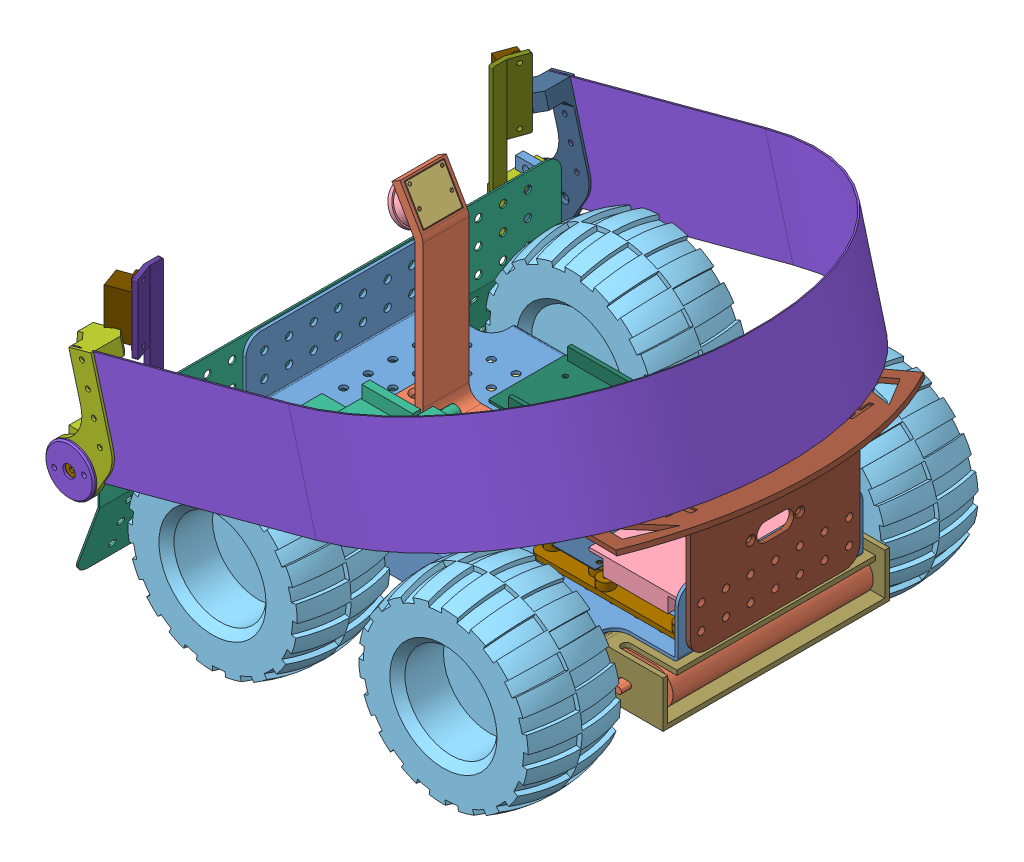
SolidWorks assembly Robot assembly, configuration Défaut. Lengths in mm.
Overall size (358.46 247.89 317.8).
40 component instances, 29 part files, 110 mates.
Components (placement in the parent):
- base-1: base [Défaut] at origin size (282.75 68.75 152.75)
- Battery-1: Battery [Default] at (120.5 -17 0) x (0 0 -1) z (1 0 0) size (145 23 45)
- motor-1: motor [Varsayılan] at (34.1153 -27.0341 -22.5727) x (-1 0 0) z (0 0 -1) size (24.4 24.4 69.3)
- motor-2: motor [Varsayılan] at (-115.8847 -27.0341 -22.5727) x (-1 0 0) z (0 0 -1) size (24.4 24.4 69.3)
- motor-3: motor [Varsayılan] at (115.8847 -27.0341 22.5727) size (24.4 24.4 69.3)
- motor-4: motor [Varsayılan] at (-34.1153 -27.0341 22.5727) size (24.4 24.4 69.3)
- Motor controller-1: Motor controller [Default] at (104.3727 13 0) x (0 0 1) z (-1 0 0) size (101.6 12 60.32)
- wheel-5: wheel [Default] at (-75.2588 -16.8727 115.8727) x (0 0 1) z (-1 0 0) size (69 120 120)
- wheel-6: wheel [Default] at (74.7412 -16.8727 115.8727) x (0 0 1) z (-0.999757 -0.022063 0) size (69 120 120)
- wheel-7: wheel [Default] at (-74.7412 -16.8727 -115.8727) x (0 0 -1) z (0.923728 0.383049 0) size (69 120 120)
- wheel-8: wheel [Default] at (75.2588 -16.8727 -115.8727) x (0 0 -1) z (0.974576 0.224058 0) size (69 120 120)
- plow-1: plow [Default] at (-145.3727 -12.6273 0) x (0 0 1) z (0 -1 0) size (300 18.07 97.16)
- Servo motor-1: Servo motor [Default] at (-155.3727 11.3727 119.9) x (-1 0 0) z (0 0 1) size (14 29 36)
- Servo motor-2: Servo motor [Default] at (-155.3727 11.3727 -119.9) x (1 0 0) z (0 0 -1) size (14 29 36)
- Cage-1: Cage [Default] at (1.6189 44.7973 0) x (0 0 1) z (-0.965926 -0.258819 0) size (310.66 70 301.4)
- H-bridge_support-1: H-bridge_support [Default] at (84.3727 0 0) x (0 0 1) z (-1 0 0) size (100 8 100)
- Fuse board-1: Fuse board [Default] at (58.3727 8 24.5) x (0 0 -1) z (1 0 0) size (49 0.5 36)
- Power board-1: Power board [Default] at (48.8727 8 -25) x (0 0 -1) z (1 0 0) size (50 1.06 25)
- Battery holder-1: Battery holder [Default] at (120 -32 0) x (0 0 -1) z (1 0 0) size (147 30 50)
- hex nut style 1 gradeab_iso-1: hex nut style 1 gradeab_iso [Hexagon Nut ISO - 4032 - M4 - W - N] at (120 3.2 -32) x (1 0 0) z (0 1 0) size (7 8.08 3.2)
- PRismino support-1: PRismino support [Default] at (-32 0 -40) x (0 0 1) z (-1 0 0) size (36 8 36)
- PRismino-1: PRismino [Default] at (-32 8 -40) x (0 0 1) z (-1 0 0) size (50 9.6 50)
- IR sensor support left-1: IR sensor support left [Défaut] at (-140.9264 106.3727 -127.6899) x (0 -1 0) z (-0.939693 0 -0.34202) size (100 22.4 6.07)
- IR sensor support right-1: IR sensor support right [Défaut] at (-143.7455 106.3727 129.7421) x (0 -1 0) z (0.939693 0 -0.34202) size (100 22.4 6.07)
- IR sensor-1: IR sensor [Default] at (-145.9686 83.8727 -122.608) x (0 -1 0) z (-0.939693 0 -0.34202) size (44.6 13 14)
- IR sensor-2: IR sensor [Default] at (-145.9686 83.8727 123.6341) x (0 -1 0) z (-0.939693 0 0.34202) size (44.6 13 14)
- Servo motor mount-1: Servo motor mount [Default] at (-145.3727 -11.1273 -117.9) x (0 1 0) z (-1 0 0) size (45 24 15.8)
- Servo motor mount-2: Servo motor mount [Default] at (-145.3727 33.8727 117.9) x (0 -1 0) z (-1 0 0) size (45 24 15.8)
- Camera support-1: Camera support [Default] at (-72 0 0) x (0 0 1) z (-1 0 0) size (30 133.98 45)
- Raspberry Pi camera-1: Raspberry Pi camera [Default] at (-77.4378 122.0885 0) x (0 0 1) z (0.5 -0.866025 0) size (25 6 24)
- Lens-1: Lens [Default] at (-81.134 116.4904 0) x (-0.5 0.866025 0) z (0 0 1) size (25 15 25)
- Raspberry Pi support-1: Raspberry Pi support [Default] at (-56 0 48) x (-1 0 0) z (0 0 -1) size (67.8 8 35.5)
- Raspberry Pi-1: Raspberry Pi [Default] at (-56 8 48) size (110.9 20.5 65.5)
- Cage servo support left-1: Cage servo support left [Default] at (-155.3727 6.8727 152.9) x (0 0 1) z (0.965926 0.258819 0) size (24 82 46.38)
- Cage servo support blocker-1: Cage servo support blocker [Default] at (-155.3727 6.8727 156.9) x (0 0 1) z (0.965926 0.258819 0) size (2 32 32)
- Servo adapter-1: Servo adapter [Default] at (-155.3727 6.8727 156.4) x (0.961499 0.274807 0) z (0 0 -1) size (8 28.8 4.8)
- Cage servo support right-2: Cage servo support right [Default] at (-155.3727 6.8727 -152.9) x (0 0 1) z (0.965926 0.258819 0) size (24 82 46.38)
- Servo adapter-2: Servo adapter [Default] at (-155.3727 6.8727 -156.4) x (-0.961499 -0.274807 0) z (0 0 1) size (8 28.8 4.8)
- Cage servo support blocker-2: Cage servo support blocker [Default] at (-155.3727 6.8727 -156.9) x (0 0 -1) z (-0.965926 -0.258819 0) size (2 32 32)
- Cage rear support-1: Cage rear support [Default] at (141.3727 39 0) x (0 0 -1) z (1 0 0) size (200 89.91 70.32)
Mates (geometry in assembly coordinates):
- Coincident4: coincident anti-aligned: plane of Battery-1 through (120.5 -17 0) normal (0 0 -1); plane of assembly through (0 0 0) normal (0 0 1)
- Concentric1: concentric aligned: cylinder of base-1 through (-83.5 -16.8727 74.3727) axis (0 0 1) radius 1.6; cylinder of motor-4 through (-83.5 -16.8727 64.3727) axis (0 0 1) radius 1
- Concentric2: concentric aligned: cylinder of base-1 through (-66.5 -16.8727 74.3727) axis (0 0 1) radius 1.6; cylinder of motor-4 through (-66.5 -16.8727 64.3727) axis (0 0 1) radius 1
- Coincident5: coincident anti-aligned: plane of base-1 through (0 73.6273 74.3727) normal (0 0 -1); plane of motor-4 through (-75.2588 -16.8727 74.3727) normal (0 0 1)
- Concentric3: concentric aligned: cylinder of base-1 through (66.5 -16.8727 74.3727) axis (0 0 1) radius 1.6; cylinder of motor-3 through (66.5 -16.8727 64.3727) axis (0 0 1) radius 1
- Concentric4: concentric aligned: cylinder of base-1 through (83.5 -16.8727 74.3727) axis (0 0 1) radius 1.6; cylinder of motor-3 through (83.5 -16.8727 64.3727) axis (0 0 1) radius 1
- Coincident6: coincident anti-aligned: plane of base-1 through (0 73.6273 74.3727) normal (0 0 -1); plane of motor-3 through (74.7412 -16.8727 74.3727) normal (0 0 1)
- Concentric5: concentric aligned: cylinder of base-1 through (83.5 -16.8727 -74.3727) axis (0 0 -1) radius 1.6; cylinder of motor-1 through (83.5 -16.8727 -64.3727) axis (0 0 -1) radius 1
- Concentric6: concentric aligned: cylinder of base-1 through (66.5 -16.8727 -74.3727) axis (0 0 -1) radius 1.6; cylinder of motor-1 through (66.5 -16.8727 -64.3727) axis (0 0 -1) radius 1
- Coincident7: coincident anti-aligned: plane of base-1 through (0 73.6273 -74.3727) normal (0 0 1); plane of motor-1 through (75.2588 -16.8727 -74.3727) normal (0 0 -1)
- Concentric7: concentric aligned: cylinder of motor-2 through (-66.5 -16.8727 -64.3727) axis (0 0 -1) radius 1; cylinder of base-1 through (-66.5 -16.8727 -74.3727) axis (0 0 -1) radius 1.6
- Concentric8: concentric aligned: cylinder of base-1 through (-83.5 -16.8727 -74.3727) axis (0 0 -1) radius 1.6; cylinder of motor-2 through (-83.5 -16.8727 -64.3727) axis (0 0 -1) radius 1
- Coincident8: coincident anti-aligned: plane of base-1 through (0 73.6273 -74.3727) normal (0 0 1); plane of motor-2 through (-74.7412 -16.8727 -74.3727) normal (0 0 -1)
- Coincident15: coincident aligned: plane of Motor controller-1 through (104.3727 13 0) normal (0 0 1); plane of assembly through (0 0 0) normal (0 0 1)
- Concentric18: concentric anti-aligned: cylinder of motor-1 through (75.2588 -16.8727 -85.8727) axis (0 0 1) radius 2; cylinder of wheel-8 through (75.2588 -16.8727 -76.8727) axis (0 0 -1) radius 5
- Coincident26: coincident anti-aligned: plane of motor-1 through (75.2588 -16.8727 -76.8727) normal (0 0 -1); plane of wheel-8 through (75.2588 -16.8727 -76.8727) normal (0 0 1)
- Coincident28: coincident aligned: plane of plow-1; plane of assembly through (0 0 0) normal (0 0 1)
- Concentric20: concentric anti-aligned: cylinder of base-1 through (-141.3727 27.3727 0) axis (1 0 0) radius 2.4; cylinder of plow-1 through (-144.3727 27.3727 0) axis (-1 0 0) radius 2.4
- Coincident37: coincident aligned: plane of Cage-1; plane of assembly through (0 0 0) normal (0 0 1)
- Distance13: distance = 3 mm anti-aligned: plane of base-1 through (-141.3727 -140.6273 0) normal (-1 0 0); plane of plow-1 through (-144.3727 -52.6273 -140) normal (1 0 0)
- Coincident45: coincident anti-aligned: plane of base-1 through (0 0 0) normal (0 1 0); plane of H-bridge_support-1 through (84.3727 0 0) normal (0 -1 0)
- Distance5: distance = 5 mm anti-aligned: plane of H-bridge_support-1 through (134.3727 3 -50) normal (1 0 0); plane of base-1 through (139.3727 -140.6273 0) normal (-1 0 0)
- Coincident47: coincident aligned: plane of H-bridge_support-1 through (84.3727 0 0) normal (0 0 1); plane of assembly through (0 0 0) normal (0 0 1)
- Concentric25: concentric anti-aligned: cylinder of Motor controller-1 through (79.3727 13 -45) axis (0 1 0) radius 1.5; cylinder of H-bridge_support-1 through (79.3727 8 -45) axis (0 -1 0) radius 5
- Distance6: distance = 10 mm anti-aligned: plane of H-bridge_support-1 through (84.3727 3 0) normal (0 1 0); plane of Motor controller-1 through (104.3727 13 0) normal (0 -1 0)
- Distance9: distance = 2 mm aligned: plane of H-bridge_support-1 through (34.3727 3 -50) normal (-1 0 0); plane of Fuse board-1 through (36.3727 18.2082 12) normal (-1 0 0)
- Distance7: distance = 5 mm aligned: plane of Fuse board-1 through (44.3727 8.5 45) normal (0 0 1); plane of H-bridge_support-1 through (34.3727 3 50) normal (0 0 1)
- Coincident52: coincident anti-aligned: plane of H-bridge_support-1 through (39.6227 8 39.5) normal (0 1 0); plane of Fuse board-1 through (58.3727 8 24.5) normal (0 -1 0)
- Distance11: distance = 2 mm aligned: plane of H-bridge_support-1 through (34.3727 3 -50) normal (-1 0 0); plane of Power board-1 through (36.3727 9.06 0) normal (-1 0 0)
- Coincident55: coincident aligned: plane of H-bridge_support-1 through (34.3727 3 -50) normal (0 0 -1); plane of Power board-1 through (36.3727 9.06 -50) normal (0 0 -1)
- Coincident56: coincident anti-aligned: plane of H-bridge_support-1 through (41.3727 8 -15) normal (0 1 0); plane of Power board-1 through (48.8727 8 -25) normal (0 -1 0)
- Coincident60: coincident anti-aligned: plane of base-1 through (0 -2 0) normal (0 -1 0); plane of Battery holder-1 through (120 -2 0) normal (0 1 0)
- Coincident61: coincident anti-aligned: plane of Battery holder-1 through (120 -32 0) normal (0 0 -1); plane of assembly through (0 0 0) normal (0 0 1)
- Distance12: distance = 12 mm anti-aligned: plane of Battery-1; plane of Battery holder-1 through (120 -5 0) normal (0 -1 0)
- Tangent9: tangent anti-aligned: cylinder of Battery-1 through (109.5 -17 65) axis (0 0 -1) radius 11.5; plane of Battery holder-1 through (98 -2 73.5) normal (1 0 0)
- Concentric28: concentric anti-aligned: cylinder of base-1 through (120 -2 32) axis (0 1 0) radius 2.4; cylinder of Battery holder-1 through (120 -5 32) axis (0 -1 0) radius 2.25
- Concentric29: concentric aligned: cylinder of base-1 through (120 -2 -32) axis (0 1 0) radius 2.4; cylinder of hex nut style 1 gradeab_iso-1 through (120 0 -32) axis (0 1 0) radius 1.65
- Coincident64: coincident anti-aligned: plane of base-1 through (0 0 0) normal (0 1 0); plane of hex nut style 1 gradeab_iso-1 through (113 0 -32) normal (0 -1 0)
- Coincident66: coincident anti-aligned: plane of PRismino support-1 through (-19 8 -27) normal (0 1 0); plane of PRismino-1 through (-32 8 -40) normal (0 -1 0)
- Concentric32: concentric aligned: cylinder of PRismino support-1 through (-19 0 -27) axis (0 1 0) radius 1.45; cylinder of PRismino-1 through (-19 8 -27) axis (0 1 0) radius 1.6
- Concentric33: concentric aligned: cylinder of PRismino support-1 through (-45 0 -53) axis (0 1 0) radius 1.45; cylinder of PRismino-1 through (-45 8 -53) axis (0 1 0) radius 1.6
- Coincident67: coincident anti-aligned: plane of base-1 through (0 0 0) normal (0 1 0); plane of PRismino support-1 through (-19 0 -27) normal (0 -1 0)
- Concentric42: concentric anti-aligned: cylinder of plow-1 through (-144.3727 11.3727 112) axis (-1 0 0) radius 2.4; cylinder of IR sensor support right-1 through (-151.4057 11.3727 112) axis (1 0 0) radius 2.25
- Coincident68: coincident anti-aligned: plane of plow-1 through (-145.3727 -52.6273 -140) normal (-1 0 0); plane of IR sensor support right-1 through (-145.3727 6.3727 107.5261) normal (1 0 0)
- Concentric43: concentric anti-aligned: cylinder of plow-1 through (-144.3727 27.3727 112) axis (-1 0 0) radius 2.4; cylinder of IR sensor support right-1 through (-151.4057 27.3727 112) axis (1 0 0) radius 2.25
- Concentric44: concentric aligned: cylinder of plow-1 through (-144.3727 11.3727 -112) axis (-1 0 0) radius 2.4; cylinder of IR sensor support left-1 through (-138.0422 11.3727 -112) axis (-1 0 0) radius 2.25
- Coincident69: coincident anti-aligned: plane of plow-1 through (-145.3727 -52.6273 -140) normal (-1 0 0); plane of IR sensor support left-1 through (-145.3727 6.3727 -115.4739) normal (1 0 0)
- Concentric45: concentric aligned: cylinder of plow-1 through (-144.3727 27.3727 -112) axis (-1 0 0) radius 2.4; cylinder of IR sensor support left-1 through (-138.0422 27.3727 -112) axis (-1 0 0) radius 2.25
- Coincident70: coincident anti-aligned: plane of IR sensor support left-1 through (-143.7455 106.3727 -128.716) normal (-0.939693 0 -0.34202); plane of IR sensor-1 through (-145.9686 83.8727 -122.608) normal (0.939693 0 0.34202)
- Concentric46: concentric anti-aligned: cylinder of IR sensor support left-1 through (-143.1495 65.3727 -121.5819) axis (-0.939693 0 -0.34202) radius 1.5; cylinder of IR sensor-1 through (-147.3782 65.3727 -123.121) axis (0.939693 0 0.34202) radius 1.6
- Concentric47: concentric anti-aligned: cylinder of IR sensor support left-1 through (-143.1495 102.3727 -121.5819) axis (-0.939693 0 -0.34202) radius 1.5; cylinder of IR sensor-1 through (-147.3782 102.3727 -123.121) axis (0.939693 0 0.34202) radius 1.6
- Coincident71: coincident anti-aligned: plane of IR sensor support right-1 through (-143.7455 106.3727 129.7421) normal (-0.939693 0 0.34202); plane of IR sensor-2 through (-145.9686 83.8727 123.6341) normal (0.939693 0 -0.34202)
- Concentric48: concentric aligned: cylinder of IR sensor support right-1 through (-145.9686 65.3727 123.6341) axis (0.939693 0 -0.34202) radius 1.5; cylinder of IR sensor-2 through (-147.3782 65.3727 124.1471) axis (0.939693 0 -0.34202) radius 1.6
- Concentric49: concentric aligned: cylinder of IR sensor support right-1 through (-145.9686 102.3727 123.6341) axis (0.939693 0 -0.34202) radius 1.5; cylinder of IR sensor-2 through (-147.3782 102.3727 124.1471) axis (0.939693 0 -0.34202) radius 1.6
- Coincident72: coincident anti-aligned: plane of plow-1 through (-145.3727 -52.6273 -140) normal (-1 0 0); plane of Servo motor mount-1 through (-145.3727 -11.1273 -117.9) normal (1 0 0)
- Concentric50: concentric aligned: cylinder of plow-1 through (-144.3727 -4.6273 -128) axis (-1 0 0) radius 2.4; cylinder of Servo motor mount-1 through (-148.3727 -4.6273 -128) axis (-1 0 0) radius 2.25
- Coincident73: coincident anti-aligned: plane of plow-1 through (-145.3727 -52.6273 -140) normal (-1 0 0); plane of Servo motor mount-2 through (-145.3727 33.8727 117.9) normal (1 0 0)
- Concentric51: concentric aligned: cylinder of plow-1 through (-144.3727 -4.6273 128) axis (-1 0 0) radius 2.4; cylinder of Servo motor mount-2 through (-148.3727 -4.6273 128) axis (-1 0 0) radius 2.25
- Coincident74: coincident anti-aligned: plane of Servo motor-2 through (-148.3727 -3.1273 -151.9) normal (1 0 0); plane of Servo motor mount-1 through (-148.3727 -11.1273 -117.9) normal (-1 0 0)
- Coincident75: coincident anti-aligned: plane of Servo motor-2 through (-148.3727 -3.1273 -151.9) normal (0 -1 0); plane of Servo motor mount-1 through (-161.1727 -3.1273 -139.9) normal (0 1 0)
- Distance14: distance = 10 mm aligned: plane of Servo motor mount-1 through (-145.3727 -11.1273 -141.9) normal (0 0 -1); plane of Servo motor-2 through (-155.3727 11.3727 -151.9) normal (0 0 -1)
- Coincident77: coincident anti-aligned: plane of Servo motor-1 through (-148.3727 -3.1273 151.9) normal (1 0 0); plane of Servo motor mount-2 through (-148.3727 33.8727 117.9) normal (-1 0 0)
- Coincident78: coincident anti-aligned: plane of Servo motor-1 through (-162.3727 -3.1273 151.9) normal (0 -1 0); plane of Servo motor mount-2 through (-161.1727 -3.1273 139.9) normal (0 1 0)
- Distance15: distance = 10 mm aligned: plane of Servo motor mount-2 through (-145.3727 33.8727 141.9) normal (0 0 1); plane of Servo motor-1 through (-155.3727 11.3727 151.9) normal (0 0 1)
- Concentric52: concentric aligned: cylinder of base-1 through (-88 -2 0) axis (0 1 0) radius 2.4; cylinder of Camera support-1 through (-88 0 0) axis (0 1 0) radius 2.5
- Coincident81: coincident anti-aligned: plane of base-1 through (0 0 0) normal (0 1 0); plane of Camera support-1 through (-72 0 0) normal (0 -1 0)
- Concentric53: concentric aligned: cylinder of base-1 through (-56 -2 0) axis (0 1 0) radius 2.4; cylinder of Camera support-1 through (-56 0 0) axis (0 1 0) radius 2.5
- Concentric54: concentric anti-aligned: cylinder of Camera support-1 through (-83.7321 114.9904 0) axis (0.866025 0.5 0) radius 10.5; cylinder of Lens-1 through (-94.7739 108.6154 0) axis (-0.866025 -0.5 0) radius 10
- Coincident82: coincident anti-aligned: plane of Camera support-1 through (-74.5 105 -50.212) normal (-0.866025 -0.5 0); plane of Lens-1 through (-86.134 125.1506 0) normal (0.866025 0.5 0)
- Coincident83: coincident anti-aligned: plane of Camera support-1 through (-24.0785 27.6675 0) normal (0.866025 0.5 0); plane of Raspberry Pi camera-1 through (-78.3038 121.5885 0) normal (-0.866025 -0.5 0)
- Distance16: distance = 0.5 mm anti-aligned: plane of Raspberry Pi camera-1 through (-84.3038 131.9808 12.5) normal (0 0 1); plane of Camera support-1 through (-84.5538 132.4138 13) normal (0 0 -1)
- Distance17: distance = 0.5 mm anti-aligned: plane of Camera support-1 through (-84.5538 132.4138 13) normal (0.5 -0.866025 0); plane of Raspberry Pi camera-1 through (-84.3038 131.9808 -12.5) normal (-0.5 0.866025 0)
- Coincident86: coincident anti-aligned: plane of Raspberry Pi support-1 through (-18.2 8 32.5) normal (0 1 0); plane of Raspberry Pi-1 through (-56 8 48) normal (0 -1 0)
- Concentric57: concentric aligned: cylinder of Raspberry Pi support-1 through (-73.3 0 58) axis (0 1 0) radius 1.175; cylinder of Raspberry Pi-1 through (-73.3 4.6 58) axis (0 1 0) radius 1.45
- Concentric58: concentric aligned: cylinder of Raspberry Pi support-1 through (-18.2 0 32.5) axis (0 1 0) radius 1.175; cylinder of Raspberry Pi-1 through (-18.2 4.6 32.5) axis (0 1 0) radius 1.45
- Coincident87: coincident anti-aligned: plane of base-1 through (0 0 0) normal (0 1 0); plane of Raspberry Pi support-1 through (-73.3 0 58) normal (0 -1 0)
- Concentric59: concentric aligned: cylinder of base-1 through (-40 -2 48) axis (0 1 0) radius 2.4; cylinder of Raspberry Pi support-1 through (-40 3 48) axis (0 1 0) radius 2.25
- Concentric60: concentric aligned: cylinder of base-1 through (-72 -2 48) axis (0 1 0) radius 2.4; cylinder of Raspberry Pi support-1 through (-72 3 48) axis (0 1 0) radius 2.25
- Distance19: distance = 1 mm anti-aligned: plane of Cage servo support left-1 through (-155.3727 6.8727 152.9) normal (0 0 -1); plane of Servo motor-1 through (-155.3727 11.3727 151.9) normal (0 0 1)
- Concentric64: concentric anti-aligned: cylinder of Servo motor-1 through (-155.3727 6.8727 155.9) axis (0 0 -1) radius 2.5; cylinder of Cage servo support left-1 through (-155.3727 6.8727 152.9) axis (0 0 1) radius 4.1
- Concentric65: concentric aligned: cylinder of plow-1 through (-144.3727 27.3727 128) axis (-1 0 0) radius 2.4; cylinder of Servo motor mount-2 through (-148.3727 27.3727 128) axis (-1 0 0) radius 2.25
- Concentric66: concentric anti-aligned: cylinder of Cage servo support left-1 through (-145.7134 9.4609 152.9) axis (0 0 -1) radius 1.7; cylinder of Cage servo support blocker-1 through (-145.7134 9.4609 156.9) axis (0 0 1) radius 1.6
- Concentric67: concentric anti-aligned: cylinder of Cage servo support left-1 through (-165.0319 4.2845 152.9) axis (0 0 -1) radius 1.7; cylinder of Cage servo support blocker-1 through (-165.0319 4.2845 156.9) axis (0 0 1) radius 1.6
- Coincident91: coincident anti-aligned: plane of Cage servo support left-1 through (-155.3727 6.8727 156.9) normal (0 0 1); plane of Cage servo support blocker-1 through (-155.3727 6.8727 156.9) normal (0 0 -1)
- Coincident92: coincident aligned: plane of Cage-1 through (-157.5973 74.6048 154.3284) normal (-0.965926 -0.258819 0); plane of Cage servo support left-1 through (-157.5973 74.6048 239.9689) normal (-0.965926 -0.258819 0)
- Coincident93: coincident aligned: plane of Cage-1 through (-16.4984 112.4121 0) normal (-0.258819 0.965926 0); plane of Cage servo support left-1 through (-143.1084 78.4871 239.9689) normal (-0.258819 0.965926 0)
- Coincident94: coincident anti-aligned: plane of Cage servo support left-1 through (-155.3727 6.8727 154.9) normal (0 0 1); plane of Servo adapter-1 through (-158.8078 18.8914 154.9) normal (0 0 -1)
- Parallel2: parallel anti-aligned: plane of Cage servo support left-1 through (-157.5019 3.4864 154.9) normal (0.933771 0.357872 0); plane of Servo adapter-1 through (-153.7118 -5.826 154.9) normal (-0.933771 -0.357872 0)
- Concentric69: concentric anti-aligned: cylinder of Servo motor-1 through (-155.3727 6.8727 155.9) axis (0 0 -1) radius 2.5; cylinder of Servo adapter-1 through (-155.3727 6.8727 152.4) axis (0 0 1) radius 1.5
- Distance20: distance = 1 mm anti-aligned: plane of Cage servo support right-2 through (-155.3727 6.8727 -152.9) normal (0 0 1); plane of Servo motor-2 through (-155.3727 11.3727 -151.9) normal (0 0 -1)
- Concentric70: concentric anti-aligned: cylinder of Servo motor-2 through (-155.3727 6.8727 -155.9) axis (0 0 1) radius 2.5; cylinder of Cage servo support right-2 through (-155.3727 6.8727 -152.9) axis (0 0 -1) radius 4.1
- Coincident98: coincident aligned: plane of Cage servo support left-1 through (-128.0333 22.2259 239.9689) normal (0.965926 0.258819 0); plane of Cage servo support right-2 through (-128.0333 22.2259 -239.9689) normal (0.965926 0.258819 0)
- Concentric72: concentric anti-aligned: cylinder of Servo motor-2 through (-155.3727 6.8727 -155.9) axis (0 0 1) radius 2.5; cylinder of Servo adapter-2 through (-155.3727 6.8727 -154.9) axis (0 0 -1) radius 4
- Coincident99: coincident anti-aligned: plane of Cage servo support right-2 through (-155.3727 6.8727 -154.9) normal (0 0 -1); plane of Servo adapter-2 through (-158.8078 18.8914 -154.9) normal (0 0 1)
- Parallel4: parallel anti-aligned: plane of Cage servo support right-2 through (-157.5019 3.4864 -154.9) normal (0.933771 0.357872 0); plane of Servo adapter-2 through (-153.7118 -5.826 -154.9) normal (-0.933771 -0.357872 0)
- Coincident101: coincident anti-aligned: plane of Cage servo support right-2 through (-155.3727 6.8727 -156.9) normal (0 0 -1); plane of Cage servo support blocker-2 through (-155.3727 6.8727 -156.9) normal (0 0 1)
- Concentric73: concentric anti-aligned: cylinder of Cage servo support right-2 through (-165.0319 4.2845 -152.9) axis (0 0 1) radius 1.7; cylinder of Cage servo support blocker-2 through (-165.0319 4.2845 -156.9) axis (0 0 -1) radius 1.6
- Concentric74: concentric anti-aligned: cylinder of Cage servo support right-2 through (-145.7134 9.4609 -152.9) axis (0 0 1) radius 1.7; cylinder of Cage servo support blocker-2 through (-145.7134 9.4609 -156.9) axis (0 0 -1) radius 1.6
- Angle1: planar angle = 0.261799 rad aligned: plane of Cage-1 through (-16.4984 112.4121 0) normal (-0.258819 0.965926 0); plane of assembly through (0 0 0) normal (0 1 0)
- Coincident102: coincident anti-aligned: plane of base-1 through (141.3727 -140.6273 0) normal (1 0 0); plane of Cage rear support-1 through (141.3727 39 0) normal (-1 0 0)
- Distance21: distance = 1 mm anti-aligned: plane of Battery holder-1 through (120 -2 0) normal (0 1 0); plane of Cage rear support-1 through (144.3727 -1 55) normal (0 -1 0)
- Coincident104: coincident anti-aligned: plane of Cage rear support-1 through (141.3727 39 0) normal (0 0 -1); plane of assembly through (0 0 0) normal (0 0 1)
- Concentric75: concentric aligned: cylinder of base-1 through (-24 -2 -48) axis (0 1 0) radius 2.4; cylinder of PRismino support-1 through (-24 3 -48) axis (0 1 0) radius 2.25
- Concentric76: concentric aligned: cylinder of base-1 through (-40 -2 -32) axis (0 1 0) radius 2.4; cylinder of PRismino support-1 through (-40 3 -32) axis (0 1 0) radius 2.25
- Concentric77: concentric anti-aligned: cylinder of motor-3 through (74.7412 -16.8727 85.8727) axis (0 0 -1) radius 2; cylinder of wheel-6 through (74.7412 -16.8727 76.8727) axis (0 0 1) radius 5
- Coincident105: coincident anti-aligned: plane of motor-3 through (74.7412 -16.8727 76.8727) normal (0 0 1); plane of wheel-6 through (74.7412 -16.8727 76.8727) normal (0 0 -1)
- Concentric78: concentric anti-aligned: cylinder of motor-4 through (-75.2588 -16.8727 85.8727) axis (0 0 -1) radius 2; cylinder of wheel-5 through (-75.2588 -16.8727 76.8727) axis (0 0 1) radius 5
- Coincident106: coincident anti-aligned: plane of motor-4 through (-75.2588 -16.8727 76.8727) normal (0 0 1); plane of wheel-5 through (-75.2588 -16.8727 76.8727) normal (0 0 -1)
- Concentric79: concentric anti-aligned: cylinder of motor-2 through (-74.7412 -16.8727 -85.8727) axis (0 0 1) radius 2; cylinder of wheel-7 through (-74.7412 -16.8727 -76.8727) axis (0 0 -1) radius 5
- Coincident107: coincident anti-aligned: plane of motor-2 through (-74.7412 -16.8727 -76.8727) normal (0 0 -1); plane of wheel-7 through (-74.7412 -16.8727 -76.8727) normal (0 0 1)
